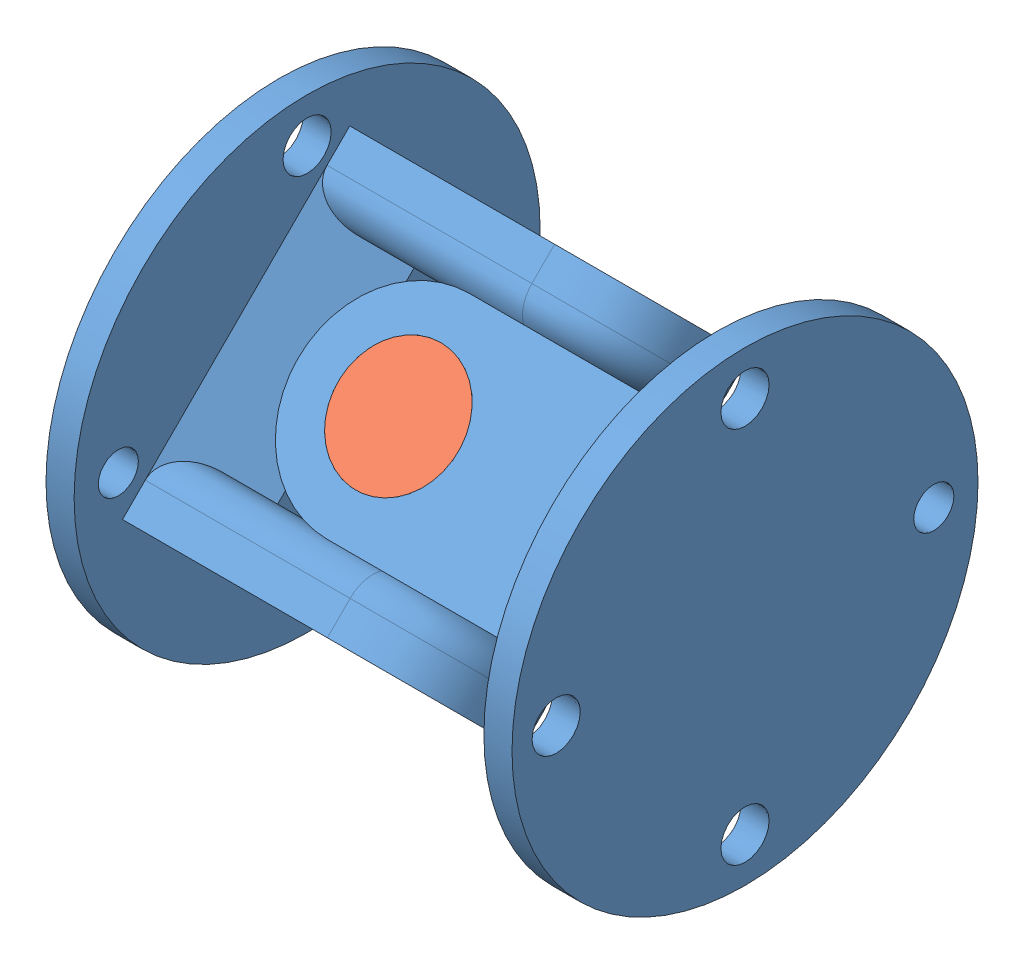
SolidWorks assembly Kruiskoppeling, configuration Default. Lengths in mm.
Overall size (58 58 58).
3 component instances, 2 part files, 4 mates.
Components (placement in the parent):
- Flensgaffel-1: Flensgaffel [Default] at (-37.4528 45.8893 54.145) size (41.5 58 58)
- Kruisstuk-1: Kruisstuk [Default] at (-8.4528 31.7471 40.0029) x (0 0.707107 0.707107) z (0 -0.707107 0.707107) size (40 15 40)
- Flensgaffel-2: Flensgaffel [Default] at (20.5472 45.8893 54.145) x (-1 0 0) z (0 0 -1) size (41.5 58 58)
Mates (geometry in assembly coordinates):
- Concentric1: concentric aligned: cylinder of Flensgaffel-1 through (-8.4528 21.9183 78.1159) axis (0 0.707107 -0.707107) radius 7.5; cylinder of Kruisstuk-1 through (-8.4528 31.7471 68.2871) axis (0 0.707107 -0.707107) radius 7.5
- Coincident1: coincident aligned: plane of Flensgaffel-1 through (4.0472 40.586 77.126) normal (0 -0.707107 0.707107); plane of Kruisstuk-1 through (-8.4528 31.7471 68.2871) normal (0 -0.707107 0.707107)
- Concentric2: concentric anti-aligned: cylinder of Kruisstuk-1 through (-8.4528 60.0314 68.2871) axis (0 -0.707107 -0.707107) radius 7.5; cylinder of Flensgaffel-2 through (-8.4528 21.9183 30.1741) axis (0 0.707107 0.707107) radius 7.5
- Coincident2: coincident aligned: plane of Kruisstuk-1 through (-8.4528 60.0314 68.2871) normal (0 0.707107 0.707107); plane of Flensgaffel-2 through (-20.9528 51.1926 77.126) normal (0 0.707107 0.707107)
